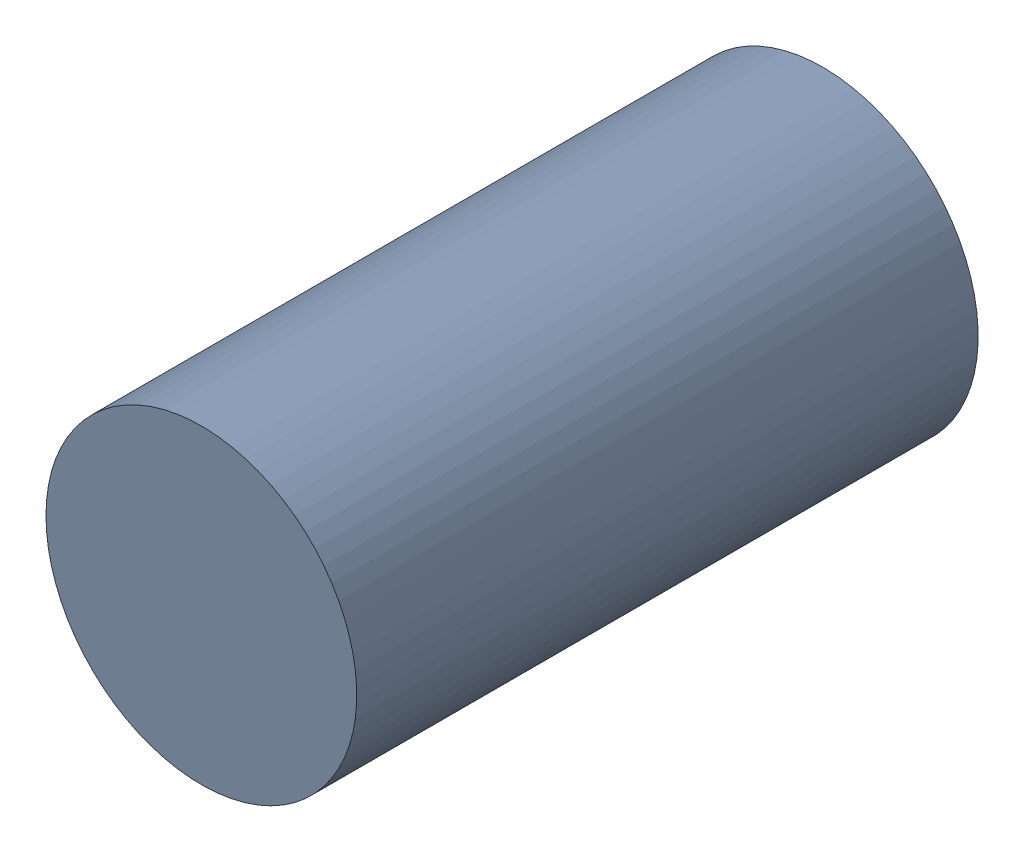
SolidWorks assembly MH7_2.step, configuration Default. Lengths in mm.
Overall size (1 1 2).
2 component instances, 1 part files, 0 mates.
Components (placement in the parent):
- 11929539264.step-1: 11929539264.step [Default] at (146.3363 110.9276 -1.5) x (-1 0 0) z (0 0 1) size (1 1 2)
  - Cylinder_2.step-7: Cylinder_2.step [Default] at origin size (1 1 2)
